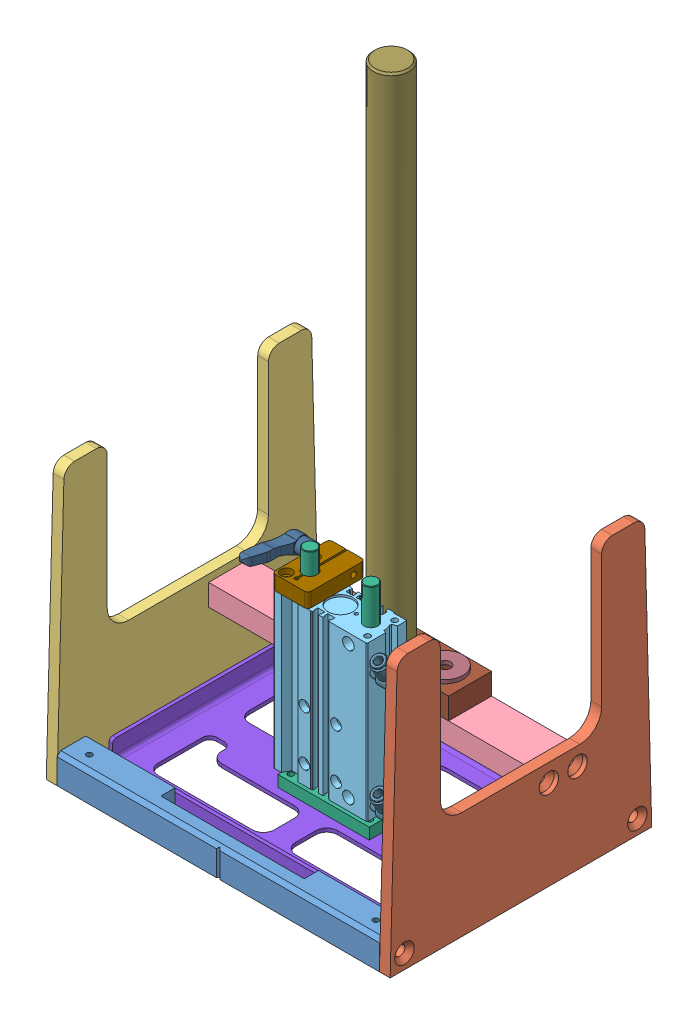
SolidWorks assembly MANDREL ASSEMBLY, configuration Default. Lengths in mm.
Overall size (304.8 552.45 231.84).
18 component instances, 14 part files, 46 mates.
Components (placement in the parent):
- MANDREL SPREADER-1: MANDREL SPREADER [Default] at (-3.1213 157.0176 298.5805) size (285.75 25.4 25.4)
- MANDREL SPREADER-2: MANDREL SPREADER [Default] at (-3.1213 157.0176 92.142) x (-1 0 0) z (0 0 -1) size (285.75 25.4 25.4)
- MANDREL SIDE PLATE 2-1: MANDREL SIDE PLATE 2 [5086-21-107] at (139.7537 191.9426 195.3612) x (0 1 0) z (1 0 0) size (241.3 231.84 9.53)
- MANDREL SIDE PLATE-1: MANDREL SIDE PLATE [5086-21-107] at (-145.9963 191.9426 195.3612) x (0 1 0) z (1 0 0) size (241.3 231.84 9.53)
- MANDREL CENTER MOUNT BAR-1: MANDREL CENTER MOUNT BAR [Default] at (-3.1213 223.6926 157.9026) size (285.75 19.05 38.1)
- CYLINDER ASSEMBLY-1: CYLINDER ASSEMBLY [MGPM20N-100] at (-3.1213 231.9926 202.8901) x (1 0 0) z (0 -1 0) size (83 36 184.5)
  - 5321-31 SMC MGPM20N-100_MGPTube-1: 5321-31 SMC MGPM20N-100_MGPTube [20M] at origin size (83 36 137)
  - 5321-31 SMC MGPM20N-100_MGPRod-1: 5321-31 SMC MGPM20N-100_MGPRod [20M] at (0 0 -52.5) size (81 30 184.5)
- CYLINDER PUSHER MOUNT-1: CYLINDER PUSHER MOUNT [Default] at (-3.1213 214.1676 184.8901) x (0 0 -1) z (1 0 0) size (50.8 50.8 76.2)
- PUSHER PLATE-1: PUSHER PLATE [Default] at (-3.1213 147.4926 196.1359) x (-1 0 0) z (0 0 -1) size (275.34 19.05 173.84)
- EJECT CYLINDER CLAMP PLATE-1: EJECT CYLINDER CLAMP PLATE [Default] at (-29.5963 306.8426 195.8401) x (-1 0 0) z (0 0 -1) size (31.75 12.7 50.8)
- ORANGE HANDLE-1: ORANGE HANDLE [Default] at (-45.4713 306.8426 180.6651) x (0 0.036993 0.999316) z (0 -0.999316 0.036993) size (46.51 30.96 14.49)
- MANDREL MNT-1: MANDREL MNT [Default] at (-3.1213 242.7426 157.9026) x (0 0 1) z (1 0 0) size (38.1 19.05 139.7)
- MANDREL STEM-1: MANDREL STEM [Default] at (-3.1213 468.1676 157.9026) x (1 0 0) z (0 -1 0) size (31.75 31.75 457.2)
- WASHER ECCENT-1: WASHER ECCENT [Default] at (-50.7463 253.8551 157.9026) x (0.993031 0 0.117855) z (-0.117855 0 0.993031) size (31.75 3.17 31.75)
- WASHER ECCENT-2: WASHER ECCENT [Default] at (44.5037 253.8551 157.9026) x (0.681183 0 -0.732113) z (0.732113 0 0.681183) size (31.75 3.17 31.75)
- ELBOW-1: ELBOW [Default] at (52.6787 275.9926 213.3901) x (0 -0.866025 -0.5) z (0 -0.5 0.866025) size (31 36.1 14.2)
- ELBOW-3: ELBOW [Default] at (52.6787 173.9926 213.3901) x (0 -0.866025 -0.5) z (0 -0.5 0.866025) size (31 36.1 14.2)
Mates (geometry in assembly coordinates):
- Parallel1: parallel: plane of MANDREL SPREADER-1 through (139.7537 169.7176 285.8805) normal (0 0 -1); plane of MANDREL SPREADER-2 through (-145.9963 169.7176 104.842) normal (0 0 1)
- Parallel2: parallel: plane of MANDREL SPREADER-1 through (139.7537 169.7176 311.2805) normal (0 1 0); plane of MANDREL SPREADER-2 through (-145.9963 169.7176 79.442) normal (0 1 0)
- Concentric2: concentric: cylinder of MANDREL SPREADER-1 through (139.7537 157.0176 298.5805) axis (1 0 0) radius 3.4; circle of MANDREL SIDE PLATE 2-1
- Concentric3: concentric: circle of MANDREL SPREADER-2; circle of MANDREL SIDE PLATE 2-1
- Concentric4: concentric: cylinder of MANDREL SPREADER-1 through (-145.9963 157.0176 298.5805) axis (-1 0 0) radius 3.4; circle of MANDREL SIDE PLATE-1
- Concentric5: concentric: cylinder of MANDREL SPREADER-2 through (-145.9963 157.0176 92.142) axis (-1 0 0) radius 3.4; circle of MANDREL SIDE PLATE-1
- Coincident1: coincident: plane of MANDREL SPREADER-2 through (-145.9963 144.3176 79.442) normal (-1 0 0); plane of MANDREL SIDE PLATE-1 through (-145.9963 144.3176 79.442) normal (1 0 0)
- Coincident2: coincident: plane of MANDREL SPREADER-2 through (139.7537 144.3176 79.442) normal (1 0 0); plane of MANDREL SIDE PLATE 2-1 through (139.7537 144.3176 79.442) normal (-1 0 0)
- Coincident3: coincident: plane of MANDREL SPREADER-1 through (139.7537 144.3176 311.2805) normal (1 0 0); plane of MANDREL SIDE PLATE 2-1 through (139.7537 144.3176 79.442) normal (-1 0 0)
- Coincident4: coincident: plane of MANDREL SPREADER-1 through (139.7537 144.3176 311.2805) normal (0 -1 0); plane of MANDREL SIDE PLATE 2-1 through (149.2787 144.3176 311.2805) normal (0 -1 0)
- Parallel3: parallel: plane of MANDREL CENTER MOUNT BAR-1 through (139.7537 233.2176 176.9526) normal (0 0 1); plane of CYLINDER PUSHER MOUNT-1 through (34.9787 214.1676 184.8901) normal (0 0 1)
- Parallel4: parallel: plane of MANDREL CENTER MOUNT BAR-1 through (139.7537 233.2176 176.9526) normal (0 1 0); plane of CYLINDER PUSHER MOUNT-1 through (34.9787 214.1676 184.8901) normal (0 1 0)
- Concentric6: concentric: cylinder of MANDREL CENTER MOUNT BAR-1 through (15.9287 214.1676 145.2026) axis (0 -1 0) radius 2.1; circle of CYLINDER PUSHER MOUNT-1
- Coincident5: coincident: plane of MANDREL CENTER MOUNT BAR-1 through (139.7537 214.1676 176.9526) normal (0 -1 0); plane of CYLINDER PUSHER MOUNT-1 through (34.9787 214.1676 184.8901) normal (0 1 0)
- Coincident6: coincident: plane of CYLINDER ASSEMBLY-1/5321-31 SMC MGPM20N-100_MGPTube-1 through (-44.6213 73.0216 184.8901) normal (0 0 -1); plane of CYLINDER PUSHER MOUNT-1 through (34.9787 214.1676 184.8901) normal (0 0 1)
- Concentric8: concentric: circle of MANDREL SIDE PLATE 2-1; cylinder of MANDREL CENTER MOUNT BAR-1 through (139.7537 223.6926 145.2026) axis (1 0 0) radius 3.4
- Coincident7: coincident: plane of MANDREL SIDE PLATE 2-1 through (139.7537 144.3176 79.442) normal (-1 0 0); plane of MANDREL CENTER MOUNT BAR-1 through (139.7537 233.2176 176.9526) normal (1 0 0)
- Concentric9: concentric: circle of MANDREL SIDE PLATE 2-1; cylinder of MANDREL CENTER MOUNT BAR-1 through (139.7537 223.6926 170.6026) axis (1 0 0) radius 3.4
- Coincident8: coincident: plane of CYLINDER ASSEMBLY-1/5321-31 SMC MGPM20N-100_MGPRod-1 through (-43.6213 147.4926 187.8901) normal (0 -1 0); plane of PUSHER PLATE-1 through (128.1967 147.4926 115.5671) normal (0 1 0)
- Coincident9: coincident: plane of CYLINDER ASSEMBLY-1/5321-31 SMC MGPM20N-100_MGPTube-1 through (-44.6213 73.0216 184.8901) normal (0 0 -1); plane of CYLINDER PUSHER MOUNT-1 through (34.9787 214.1676 184.8901) normal (0 0 1)
- Coincident10: coincident: plane of MANDREL SPREADER-1 through (139.7537 144.3176 311.2805) normal (0 -1 0); plane of PUSHER PLATE-1 through (128.1967 144.3176 115.5671) normal (0 -1 0)
- Concentric13: concentric: cylinder of CYLINDER ASSEMBLY-1/5321-31 SMC MGPM20N-100_MGPRod-1 through (31.8787 331.9926 211.8901) axis (0 -1 0) radius 2.5; circle of PUSHER PLATE-1
- Concentric14: concentric: cylinder of CYLINDER ASSEMBLY-1/5321-31 SMC MGPM20N-100_MGPRod-1 through (-38.1213 331.9926 211.8901) axis (0 -1 0) radius 2.5; circle of PUSHER PLATE-1
- Concentric15: concentric: cylinder of CYLINDER ASSEMBLY-1/5321-31 SMC MGPM20N-100_MGPRod-1 through (-30.1213 348.9632 202.8901) axis (0 -1 0) radius 6; cylinder of EJECT CYLINDER CLAMP PLATE-1 through (-30.1213 300.4916 202.8901) axis (0 1 0) radius 6
- Coincident11: coincident: plane of CYLINDER ASSEMBLY-1/5321-31 SMC MGPM20N-100_MGPTube-1 through (-3.1213 300.4926 202.8901) normal (0 1 0); plane of EJECT CYLINDER CLAMP PLATE-1 through (-13.7213 300.4926 170.4401) normal (0 -1 0)
- Parallel5: parallel: plane of CYLINDER ASSEMBLY-1/5321-31 SMC MGPM20N-100_MGPTube-1 through (-34.1572 300.4926 214.8901) normal (0 0 1); plane of EJECT CYLINDER CLAMP PLATE-1 through (-45.4713 313.1926 221.2401) normal (0 0 1)
- Concentric16: concentric: cylinder of EJECT CYLINDER CLAMP PLATE-1 through (-45.4713 306.8426 180.6651) axis (-1 0 0) radius 3.3735; cylinder of ORANGE HANDLE-1 through (-45.4713 306.8426 180.6651) axis (-1 0 0) radius 5
- Coincident12: coincident: plane of EJECT CYLINDER CLAMP PLATE-1 through (-45.4713 300.4926 170.4401) normal (-1 0 0); plane of ORANGE HANDLE-1 through (-45.4713 307.0165 185.3618) normal (1 0 0)
- Parallel6: parallel: plane of EJECT CYLINDER CLAMP PLATE-1 through (-13.7213 313.1926 170.4401) normal (0 1 0); plane of ORANGE HANDLE-1 through (-45.4713 311.6905 217.0106) normal (0 1 0)
- Concentric17: concentric: cylinder of MANDREL CENTER MOUNT BAR-1 through (44.5037 233.2176 157.9026) axis (0 1 0) radius 4.25; circle of MANDREL MNT-1
- Concentric18: concentric: circle of MANDREL CENTER MOUNT BAR-1; circle of MANDREL MNT-1
- Concentric19: concentric: circle of MANDREL MNT-1; cylinder of MANDREL STEM-1 through (-3.1213 239.5676 157.9026) axis (0 1 0) radius 15.875
- Coincident14: coincident: plane of MANDREL CENTER MOUNT BAR-1 through (139.7537 233.2176 176.9526) normal (0 1 0); plane of MANDREL MNT-1 through (66.7287 233.2176 138.8526) normal (0 -1 0)
- Parallel7: parallel: plane of MANDREL MNT-1 through (6.4248 220.2131 145.1391) normal (0 0 1); plane of MANDREL STEM-1 through (-12.6463 255.4426 145.2026) normal (0 0 -1)
- Coincident16: coincident: plane of MANDREL MNT-1 through (-3.1213 239.5676 157.9026) normal (0 1 0); plane of MANDREL STEM-1 through (-3.1213 239.5676 157.9026) normal (0 -1 0)
- Concentric20: concentric: cylinder of MANDREL MNT-1 through (-50.7463 252.2686 157.9026) axis (0 -1 0) radius 9.525; circle of WASHER ECCENT-1
- Concentric21: concentric: circle of MANDREL MNT-1; circle of WASHER ECCENT-2
- Coincident17: coincident: plane of MANDREL MNT-1 through (66.7287 252.2676 138.8526) normal (0 1 0); plane of WASHER ECCENT-1 through (-50.7463 252.2676 157.9026) normal (0 -1 0)
- Coincident18: coincident: plane of MANDREL MNT-1 through (66.7287 252.2676 138.8526) normal (0 1 0); plane of WASHER ECCENT-2 through (44.5037 252.2676 157.9026) normal (0 -1 0)
- Concentric22: concentric: circle of CYLINDER ASSEMBLY-1/5321-31 SMC MGPM20N-100_MGPTube-1; circle of ELBOW-1
- Concentric23: concentric: circle of CYLINDER ASSEMBLY-1/5321-31 SMC MGPM20N-100_MGPTube-1; cone of ELBOW-3 through (38.6339 173.9926 213.3901) axis (-1 0 0)
- Coincident19: coincident: plane of CYLINDER ASSEMBLY-1/5321-31 SMC MGPM20N-100_MGPTube-1 through (38.3787 73.0216 220.8901) normal (1 0 0); plane of ELBOW-3 through (38.3787 175.9357 219.9187) normal (-1 0 0)
- Coincident20: coincident: plane of CYLINDER ASSEMBLY-1/5321-31 SMC MGPM20N-100_MGPTube-1 through (38.3787 73.0216 220.8901) normal (1 0 0); plane of ELBOW-1 through (38.3787 277.7556 219.9697) normal (-1 0 0)
- Distance4: distance = 3.4 mm: plane of CYLINDER ASSEMBLY-1/5321-31 SMC MGPM20N-100_MGPTube-1 through (38.3787 73.0216 220.8901) normal (1 0 0); plane of CYLINDER PUSHER MOUNT-1 through (34.9787 166.5426 181.7151) normal (1 0 0)
- Parallel8: parallel: plane of CYLINDER ASSEMBLY-1/5321-31 SMC MGPM20N-100_MGPTube-1 through (-3.1213 300.4926 202.8901) normal (0 1 0); plane of ELBOW-1 through (61.8348 281.9926 209.926) normal (0 1 0)
- Parallel9: parallel: plane of CYLINDER ASSEMBLY-1/5321-31 SMC MGPM20N-100_MGPTube-1 through (-3.1213 300.4926 202.8901) normal (0 1 0); plane of ELBOW-3 through (61.8348 179.9926 209.926) normal (0 1 0)
